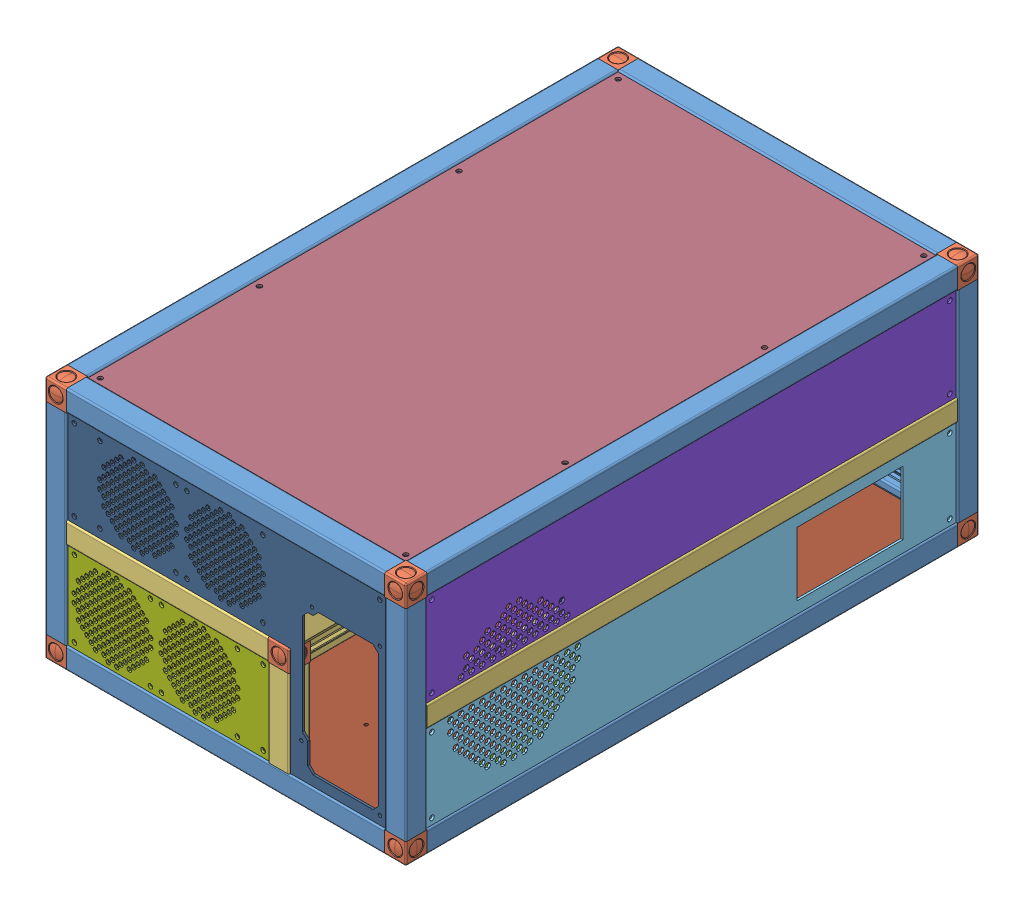
SolidWorks assembly Skeleton, configuration Default. Lengths in mm.
Overall size (341 231 541).
77 component instances, 16 part files, 227 mates.
Components (placement in the parent):
- BI010-A - BoschProfile 2NVS-20: BI010-A - BoschProfile 2NVS [L=300] at (-20 10 10) x (0 -1 0) z (-1 0 0) size (20 20 300)
- BI010-A - BoschProfile 2NVS-21: BI010-A - BoschProfile 2NVS [L=300] at (-20 10 530) x (0 0 1) z (-1 0 0) size (20 20 300)
- BI010-A - BoschProfile 2NVS-22: BI010-A - BoschProfile 2NVS [L=500] at (-10 10 20) size (20 20 500)
- BI010-A - BoschProfile 2NVS-23: BI010-A - BoschProfile 2NVS [L=500] at (-330 10 520) x (-1 0 0) z (0 0 -1) size (20 20 500)
- BI010-A - BoschProfile 2NVS-17: BI010-A - BoschProfile 2NVS [L=200] at (-330 -790 530) x (0 0 1) z (0 1 0) size (20 20 190)
- BI010-A - BoschProfile 2NVS-19: BI010-A - BoschProfile 2NVS [L=200] at (-10 -790 10) x (0 0 -1) z (0 1 0) size (20 20 190)
- BI010-A - BoschProfile 2NVS-18: BI010-A - BoschProfile 2NVS [L=200] at (-330 -790 10) x (-1 0 0) z (0 1 0) size (20 20 190)
- BI007-A - Cubic Connector 20x20-12: BI007-A - Cubic Connector 20x20 [Default] at (-20 10 10) x (-1 0 0) z (0 0 -1) size (33 33 33)
- BI007-A - Cubic Connector 20x20-13: BI007-A - Cubic Connector 20x20 [Default] at (-330 10 20) x (0 0 1) z (-1 0 0) size (33 33 33)
- BI010-A - BoschProfile 2NVS-13: BI010-A - BoschProfile 2NVS [L=200] at (-10 -790 530) x (1 0 0) z (0 1 0) size (20 20 190)
- BI007-A - Cubic Connector 20x20-7: BI007-A - Cubic Connector 20x20 [Default] at (-10 10 520) x (0 0 -1) z (1 0 0) size (33 33 33)
- BI007-A - Cubic Connector 20x20-8: BI007-A - Cubic Connector 20x20 [Default] at (-320 10 530) size (33 33 33)
- BI007-A - Cubic Connector 20x20-9: BI007-A - Cubic Connector 20x20 [Default] at (-10 220 520) x (0 0 -1) z (0 1 0) size (33 33 33)
- BI007-A - Cubic Connector 20x20-6: BI007-A - Cubic Connector 20x20 [Default] at (-320 220 530) x (1 0 0) z (0 1 0) size (33 33 33)
- BI007-A - Cubic Connector 20x20-10: BI007-A - Cubic Connector 20x20 [Default] at (-330 220 20) x (0 0 1) z (0 1 0) size (33 33 33)
- BI007-A - Cubic Connector 20x20-11: BI007-A - Cubic Connector 20x20 [Default] at (-20 220 10) x (-1 0 0) z (0 1 0) size (33 33 33)
- BI010-A - BoschProfile 2NVS-15: BI010-A - BoschProfile 2NVS [L=500] at (-10 220 20) x (0 1 0) z (0 0 1) size (20 20 500)
- BI010-A - BoschProfile 2NVS-14: BI010-A - BoschProfile 2NVS [L=500] at (-330 220 520) x (0 1 0) z (0 0 -1) size (20 20 500)
- BI010-A - BoschProfile 2NVS-12: BI010-A - BoschProfile 2NVS [L=300] at (-20 220 10) x (0 0 -1) z (-1 0 0) size (20 20 300)
- BI010-A - BoschProfile 2NVS-16: BI010-A - BoschProfile 2NVS [L=300] at (-20 220 530) x (0 1 0) z (-1 0 0) size (20 20 300)
- BI011-A - BoschProfile 3N-7: BI011-A - BoschProfile 3N [L = 300] at (-20 112 10) x (0 0 -1) z (-1 0 0) size (20 20 300)
- BI011-A - BoschProfile 3N-18: BI011-A - BoschProfile 3N [L = 500] at (-330 112 520) x (-1 0 0) z (0 0 -1) size (20 20 500)
- BI011-A - BoschProfile 3N-19: BI011-A - BoschProfile 3N [L = 82] at (-120 102 530) x (0 0 1) z (0 -1 0) size (20 20 82)
- BI011-A - BoschProfile 3N-20: BI011-A - BoschProfile 3N [L = 500] at (-120 112 520) x (0 1 0) z (0 0 -1) size (20 20 500)
- BI011-A - BoschProfile 3N-16: BI011-A - BoschProfile 3N [L = 180] at (-130 112 530) x (0 0 1) z (-1 0 0) size (20 20 190)
- BI007-A - Cubic Connector 20x20-14: BI007-A - Cubic Connector 20x20 [Default] at (-120 102 530) x (0 -1 0) z (1 0 0) size (33 33 33)
- BI011-A - BoschProfile 3N-17: BI011-A - BoschProfile 3N [L = 500] at (-10 112 520) x (1 0 0) z (0 0 -1) size (20 20 500)
- BI008-A - Bracket-S 20X20-21: BI008-A - Bracket-S 20X20 [Default] at (-320 122 530) x (0 0 -1) z (0 1 0) size (15.51 28.51 28.51)
- BI008-A - Bracket-S 20X20-22: BI008-A - Bracket-S 20X20 [Default] at (-130 20 530) x (0 0 -1) z (-1 0 0) size (15.51 28.51 28.51)
- BI008-A - Bracket-S 20X20-25: BI008-A - Bracket-S 20X20 [Default] at (-330 102 520) x (1 0 0) z (0 -1 0) size (15.51 28.51 28.51)
- BI008-A - Bracket-S 20X20-20: BI008-A - Bracket-S 20X20 [Default] at (-330 102 20) size (15.51 28.51 28.51)
- BI008-A - Bracket-S 20X20-23: BI008-A - Bracket-S 20X20 [Default] at (-10 102 20) x (-1 0 0) z (0 -1 0) size (15.51 28.51 28.51)
- BI008-A - Bracket-S 20X20-24: BI008-A - Bracket-S 20X20 [Default] at (-10 102 520) x (-1 0 0) z (0 0 -1) size (15.51 28.51 28.51)
- BI008-A - Bracket-S 20X20-18: BI008-A - Bracket-S 20X20 [Default] at (-20 102 10) x (0 0 1) z (-1 0 0) size (15.51 28.51 28.51)
- BI008-A - Bracket-S 20X20-17: BI008-A - Bracket-S 20X20 [Default] at (-320 102 10) x (0 0 1) z (0 -1 0) size (15.51 28.51 28.51)
- BI008-A - Bracket-S 20X20-15: BI008-A - Bracket-S 20X20 [Default] at (-130 112 20) x (0 1 0) z (-1 0 0) size (15.51 28.51 28.51)
- BI011-A - BoschProfile 3N-15: BI011-A - BoschProfile 3N [L = 300] at (-20 10 330) x (0 -1 0) z (-1 0 0) size (20 20 300)
- BI008-A - Bracket-S 20X20-16: BI008-A - Bracket-S 20X20 [Default] at (-320 10 340) x (0 1 0) z (0 0 1) size (15.51 28.51 28.51)
- BI008-A - Bracket-S 20X20-19: BI008-A - Bracket-S 20X20 [Default] at (-20 10 340) x (0 1 0) z (-1 0 0) size (15.51 28.51 28.51)
- CR020-A - PanelLaserBox1-1: CR020-A - PanelLaserBox1 [Default] at (-338.5 102 20) x (0 0 1) z (0 1 0) size (500 2 82)
- CR020-A - PanelLaserBox1-2: CR020-A - PanelLaserBox1 [FanSide] at (-1.5 102 520) x (0 0 -1) z (0 1 0) size (500 2 82)
- CR021-A - PanelLaserBox2-1: CR021-A - PanelLaserBox2 [Default] at (-320 20 1.5) x (1 0 0) z (0 -1 0) size (300 2 82)
- CR022-A - PanelLaserBox3-1: CR022-A - PanelLaserBox3 [Default] at (-320 20 536.5) x (1 0 0) z (0 -1 0) size (190 2 82)
- CR023-A - PanelLaserBox4-1: CR023-A - PanelLaserBox4 [FanSide] at (-3.5 210 20) x (0 0 1) z (0 1 0) size (500 2 88)
- CR023-A - PanelLaserBox4-2: CR023-A - PanelLaserBox4 [Default] at (-336.5 210 520) x (0 0 -1) z (0 1 0) size (500 2 88)
- CR024-A - PanelLaserBox5-1: CR024-A - PanelLaserBox5 [Default] at (-320 210 3.5) x (1 0 0) z (0 1 0) size (300 2 88)
- CR025-A - PanelLaserBox6-1: CR025-A - PanelLaserBox6 [Default] at (-110 122 536.5) x (1 0 0) z (0 -1 0) size (300 2 190)
- CR026-A - PanelLaserBox7-2: CR026-A - PanelLaserBox7 [Default] at (-170 22 270) x (0 0 -1) z (1 0 0) size (530 2 330)
- CR027-A - PanelLaserBox8-2: CR027-A - PanelLaserBox8 [Default] at (-170 124 270) x (0 0 -1) z (1 0 0) size (530 2 330)
- CR028-A - PanelLaserBox9-2: CR028-A - PanelLaserBox9 [Default] at (-170 228.5 270) x (0 0 -1) z (1 0 0) size (500 2 300)
- PP010-A - Plate Holder-57: PP010-A - Plate Holder [Default] at (-330 15.4 13.4) x (1 0 0) z (0 -1 0) size (12.3 11.8 14.6)
- PP010-A - Plate Holder-59: PP010-A - Plate Holder [Default] at (-330 15.4 501.6) x (1 0 0) z (0 -1 0) size (12.3 11.8 14.6)
- PP010-A - Plate Holder-58: PP010-A - Plate Holder [Default] at (-13.4 15.4 10) x (0 0 1) z (0 -1 0) size (12.3 11.8 14.6)
- PP010-A - Plate Holder-60: PP010-A - Plate Holder [Default] at (-10 15.4 526.6) x (-1 0 0) z (0 -1 0) size (12.3 11.8 14.6)
- PP010-A - Plate Holder-63: PP010-A - Plate Holder [Default] at (-330 117.4 13.4) x (1 0 0) z (0 -1 0) size (12.3 11.8 14.6)
- PP010-A - Plate Holder-61: PP010-A - Plate Holder [Default] at (-13.4 117.4 10) x (0 0 1) z (0 -1 0) size (12.3 11.8 14.6)
- PP010-A - Plate Holder-62: PP010-A - Plate Holder [Default] at (-10 117.4 526.6) x (-1 0 0) z (0 -1 0) size (12.3 11.8 14.6)
- PP010-A - Plate Holder-73: PP010-A - Plate Holder [Default] at (-15.4 220 526.6) x (0 -1 0) z (1 0 0) size (12.3 11.8 14.6)
- PP010-A - Plate Holder-74: PP010-A - Plate Holder [Default] at (-324.6 220 13.4) x (0 -1 0) z (-1 0 0) size (12.3 11.8 14.6)
- PP010-A - Plate Holder-68: PP010-A - Plate Holder [Default] at (-326.6 214.6 10) x (0 0 1) z (0 1 0) size (12.3 11.8 14.6)
- PP010-A - Plate Holder-75: PP010-A - Plate Holder [Default] at (-13.4 214.6 530) x (0 0 -1) z (0 1 0) size (12.3 11.8 14.6)
- PP010-A - Plate Holder-67: PP010-A - Plate Holder [Default] at (-330 214.6 526.6) x (1 0 0) z (0 1 0) size (12.3 11.8 14.6)
- PP010-A - Plate Holder-69: PP010-A - Plate Holder [Default] at (-10 214.6 13.4) x (-1 0 0) z (0 1 0) size (12.3 11.8 14.6)
- PP010-A - Plate Holder-64: PP010-A - Plate Holder [Default] at (-123.4 106.6 530) x (0 0 -1) z (0 1 0) size (12.3 11.8 14.6)
- PP010-A - Plate Holder-65: PP010-A - Plate Holder [Default] at (-301.6 15.4 10) x (0 0 1) z (0 -1 0) size (12.3 11.8 14.6)
- PP010-A - Plate Holder-72: PP010-A - Plate Holder [Default] at (-301.6 117.4 10) x (0 0 1) z (0 -1 0) size (12.3 11.8 14.6)
- PP010-A - Plate Holder-70: PP010-A - Plate Holder [Default] at (-38.4 214.6 10) x (0 0 1) z (0 1 0) size (12.3 11.8 14.6)
- PP010-A - Plate Holder-71: PP010-A - Plate Holder [Default] at (-10 15.4 38.4) x (-1 0 0) z (0 -1 0) size (12.3 11.8 14.6)
- PP010-A - Plate Holder-66: PP010-A - Plate Holder [Default] at (-10 117.4 38.4) x (-1 0 0) z (0 -1 0) size (12.3 11.8 14.6)
- PP010-A - Plate Holder-41: PP010-A - Plate Holder [Default] at (-10 214.6 501.6) x (-1 0 0) z (0 1 0) size (12.3 11.8 14.6)
- PP010-A - Plate Holder-43: PP010-A - Plate Holder [Default] at (-301.6 214.6 530) x (0 0 -1) z (0 1 0) size (12.3 11.8 14.6)
- PP010-A - Plate Holder-54: PP010-A - Plate Holder [Default] at (-330 117.4 501.6) x (1 0 0) z (0 -1 0) size (12.3 11.8 14.6)
- PP010-A - Plate Holder-55: PP010-A - Plate Holder [Default] at (-330 214.6 38.4) x (1 0 0) z (0 1 0) size (12.3 11.8 14.6)
- PP010-A - Plate Holder-56: PP010-A - Plate Holder [Default] at (-324.6 220 501.6) x (0 -1 0) z (-1 0 0) size (12.3 11.8 14.6)
- PP010-A - Plate Holder-53: PP010-A - Plate Holder [Default] at (-15.4 220 38.4) x (0 -1 0) z (1 0 0) size (12.3 11.8 14.6)
- PP011-A - PSU Fan Guide Top-1: PP011-A - PSU Fan Guide Top [Default] at (-16.5 97 436.5) x (0 0 -1) z (0 -1 0) size (142.7 16 46)
- PP012-A - PSU Fan Guide Bottom-1: PP012-A - PSU Fan Guide Bottom [Default] at (-16.5 102 436.5) x (0 0 -1) z (0 -1 0) size (148.33 16.5 75.99)
Mates (geometry in assembly coordinates):
- Coincident77: coincident: plane of BI007-A - Cubic Connector 20x20-12 through (-10 10 0) normal (0 0 -1); plane of assembly through (0 0 0) normal (0 0 1)
- Coincident78: coincident: plane of BI007-A - Cubic Connector 20x20-12 through (-10 0 10) normal (0 -1 0); plane of assembly through (0 0 0) normal (0 1 0)
- Coincident79: coincident: plane of BI007-A - Cubic Connector 20x20-12 through (0 10 10) normal (1 0 0); plane of assembly through (0 0 0) normal (1 0 0)
- Coincident80: coincident: plane of BI010-A - BoschProfile 2NVS-20 through (-1020 18.5 0) normal (0 0 -1); plane of BI007-A - Cubic Connector 20x20-12 through (-10 10 0) normal (0 0 -1)
- Coincident81: coincident: plane of BI010-A - BoschProfile 2NVS-20 through (-20 18.5 18.5) normal (1 0 0); plane of BI007-A - Cubic Connector 20x20-12 through (-20 10 10) normal (-1 0 0)
- Coincident82: coincident: plane of BI010-A - BoschProfile 2NVS-20 through (-1020 0 1.5) normal (0 -1 0); plane of BI007-A - Cubic Connector 20x20-12 through (-10 0 10) normal (0 -1 0)
- Coincident83: coincident: plane of BI010-A - BoschProfile 2NVS-22 through (0 1.5 1020) normal (1 0 0); plane of BI007-A - Cubic Connector 20x20-12 through (0 10 10) normal (1 0 0)
- Coincident84: coincident: plane of BI010-A - BoschProfile 2NVS-22 through (-18.5 0 1020) normal (0 -1 0); plane of BI007-A - Cubic Connector 20x20-12 through (-10 0 10) normal (0 -1 0)
- Coincident85: coincident: plane of BI010-A - BoschProfile 2NVS-22 through (-18.5 18.5 20) normal (0 0 -1); plane of BI007-A - Cubic Connector 20x20-12 through (-10 10 20) normal (0 0 1)
- Coincident86: coincident: plane of BI010-A - BoschProfile 2NVS-19 through (-1.5 210 0) normal (0 0 -1); plane of BI007-A - Cubic Connector 20x20-12 through (-10 10 0) normal (0 0 -1)
- Coincident87: coincident: plane of BI010-A - BoschProfile 2NVS-19 through (0 210 18.5) normal (1 0 0); plane of BI007-A - Cubic Connector 20x20-12 through (0 10 10) normal (1 0 0)
- Coincident88: coincident: plane of BI010-A - BoschProfile 2NVS-19 through (-18.5 20 18.5) normal (0 -1 0); plane of BI007-A - Cubic Connector 20x20-12 through (-10 20 10) normal (0 1 0)
- Coincident89: coincident: plane of BI010-A - BoschProfile 2NVS-20 through (-1020 18.5 0) normal (0 0 -1); plane of BI007-A - Cubic Connector 20x20-13 through (-330 10 0) normal (0 0 -1)
- Coincident90: coincident: plane of BI010-A - BoschProfile 2NVS-20 through (-1020 0 1.5) normal (0 -1 0); plane of BI007-A - Cubic Connector 20x20-13 through (-330 0 10) normal (0 -1 0)
- Coincident91: coincident: plane of BI010-A - BoschProfile 2NVS-20 through (-320 18.5 18.5) normal (-1 0 0); plane of BI007-A - Cubic Connector 20x20-13 through (-320 10 10) normal (1 0 0)
- Coincident92: coincident: plane of BI010-A - BoschProfile 2NVS-23 through (-321.5 18.5 20) normal (0 0 -1); plane of BI007-A - Cubic Connector 20x20-13 through (-330 10 20) normal (0 0 1)
- Coincident93: coincident: plane of BI010-A - BoschProfile 2NVS-23 through (-340 1.5 -480) normal (-1 0 0); plane of BI007-A - Cubic Connector 20x20-13 through (-340 10 10) normal (-1 0 0)
- Coincident94: coincident: plane of BI010-A - BoschProfile 2NVS-23 through (-321.5 0 -480) normal (0 -1 0); plane of BI007-A - Cubic Connector 20x20-13 through (-330 0 10) normal (0 -1 0)
- Coincident95: coincident: plane of BI010-A - BoschProfile 2NVS-22 through (0 1.5 1020) normal (1 0 0); plane of BI007-A - Cubic Connector 20x20-7 through (0 10 530) normal (1 0 0)
- Coincident96: coincident: plane of BI010-A - BoschProfile 2NVS-22 through (-18.5 18.5 520) normal (0 0 1); plane of BI007-A - Cubic Connector 20x20-7 through (-10 10 520) normal (0 0 -1)
- Coincident97: coincident: plane of BI010-A - BoschProfile 2NVS-22 through (-18.5 0 1020) normal (0 -1 0); plane of BI007-A - Cubic Connector 20x20-7 through (-10 0 530) normal (0 -1 0)
- Coincident98: coincident: plane of BI010-A - BoschProfile 2NVS-21 through (-20 18.5 521.5) normal (1 0 0); plane of BI007-A - Cubic Connector 20x20-7 through (-20 10 530) normal (-1 0 0)
- Coincident99: coincident: plane of BI010-A - BoschProfile 2NVS-21 through (-1020 1.5 540) normal (0 0 1); plane of BI007-A - Cubic Connector 20x20-7 through (-10 10 540) normal (0 0 1)
- Coincident100: coincident: plane of BI010-A - BoschProfile 2NVS-21 through (-1020 0 521.5) normal (0 -1 0); plane of BI007-A - Cubic Connector 20x20-7 through (-10 0 530) normal (0 -1 0)
- Coincident101: coincident: plane of BI010-A - BoschProfile 2NVS-23 through (-321.5 0 -480) normal (0 -1 0); plane of BI007-A - Cubic Connector 20x20-8 through (-330 0 530) normal (0 -1 0)
- Coincident102: coincident: plane of BI010-A - BoschProfile 2NVS-23 through (-321.5 18.5 520) normal (0 0 1); plane of BI007-A - Cubic Connector 20x20-8 through (-330 10 520) normal (0 0 -1)
- Coincident103: coincident: plane of BI010-A - BoschProfile 2NVS-23 through (-340 1.5 -480) normal (-1 0 0); plane of BI007-A - Cubic Connector 20x20-8 through (-340 10 530) normal (-1 0 0)
- Coincident104: coincident: plane of BI010-A - BoschProfile 2NVS-13 through (0 210 538.5) normal (1 0 0); plane of BI007-A - Cubic Connector 20x20-7 through (0 10 530) normal (1 0 0)
- Coincident105: coincident: plane of BI010-A - BoschProfile 2NVS-13 through (-18.5 210 540) normal (0 0 1); plane of BI007-A - Cubic Connector 20x20-7 through (-10 10 540) normal (0 0 1)
- Coincident106: coincident: plane of BI010-A - BoschProfile 2NVS-13 through (-18.5 20 521.5) normal (0 -1 0); plane of BI007-A - Cubic Connector 20x20-7 through (-10 20 530) normal (0 1 0)
- Coincident107: coincident: plane of BI010-A - BoschProfile 2NVS-17 through (-338.5 210 540) normal (0 0 1); plane of BI007-A - Cubic Connector 20x20-8 through (-330 10 540) normal (0 0 1)
- Coincident108: coincident: plane of BI010-A - BoschProfile 2NVS-17 through (-340 210 521.5) normal (-1 0 0); plane of BI007-A - Cubic Connector 20x20-8 through (-340 10 530) normal (-1 0 0)
- Coincident109: coincident: plane of BI010-A - BoschProfile 2NVS-17 through (-321.5 20 521.5) normal (0 -1 0); plane of BI007-A - Cubic Connector 20x20-8 through (-330 20 530) normal (0 1 0)
- Coincident110: coincident: plane of BI010-A - BoschProfile 2NVS-18 through (-321.5 210 0) normal (0 0 -1); plane of BI007-A - Cubic Connector 20x20-13 through (-330 10 0) normal (0 0 -1)
- Coincident111: coincident: plane of BI010-A - BoschProfile 2NVS-18 through (-340 210 1.5) normal (-1 0 0); plane of BI007-A - Cubic Connector 20x20-13 through (-340 10 10) normal (-1 0 0)
- Coincident112: coincident: plane of BI010-A - BoschProfile 2NVS-18 through (-321.5 20 18.5) normal (0 -1 0); plane of BI007-A - Cubic Connector 20x20-13 through (-330 20 10) normal (0 1 0)
- Coincident113: coincident: plane of BI010-A - BoschProfile 2NVS-13 through (0 210 538.5) normal (1 0 0); plane of BI007-A - Cubic Connector 20x20-9 through (0 220 530) normal (1 0 0)
- Coincident114: coincident: plane of BI010-A - BoschProfile 2NVS-13 through (-18.5 210 540) normal (0 0 1); plane of BI007-A - Cubic Connector 20x20-9 through (-10 220 540) normal (0 0 1)
- Coincident115: coincident: plane of BI010-A - BoschProfile 2NVS-13 through (-18.5 210 521.5) normal (0 1 0); plane of BI007-A - Cubic Connector 20x20-9 through (-10 210 530) normal (0 -1 0)
- Coincident116: coincident: plane of BI010-A - BoschProfile 2NVS-13 through (-18.5 210 521.5) normal (0 1 0); plane of BI007-A - Cubic Connector 20x20-6 through (-330 210 530) normal (0 -1 0)
- Coincident118: coincident: plane of BI010-A - BoschProfile 2NVS-17 through (-338.5 210 540) normal (0 0 1); plane of BI007-A - Cubic Connector 20x20-6 through (-330 220 540) normal (0 0 1)
- Coincident119: coincident: plane of BI010-A - BoschProfile 2NVS-17 through (-340 210 521.5) normal (-1 0 0); plane of BI007-A - Cubic Connector 20x20-6 through (-340 220 530) normal (-1 0 0)
- Coincident120: coincident: plane of BI010-A - BoschProfile 2NVS-13 through (-18.5 210 521.5) normal (0 1 0); plane of BI007-A - Cubic Connector 20x20-10 through (-330 210 10) normal (0 -1 0)
- Coincident124: coincident: plane of BI010-A - BoschProfile 2NVS-18 through (-340 210 1.5) normal (-1 0 0); plane of BI007-A - Cubic Connector 20x20-10 through (-340 220 10) normal (-1 0 0)
- Coincident125: coincident: plane of BI010-A - BoschProfile 2NVS-18 through (-321.5 210 0) normal (0 0 -1); plane of BI007-A - Cubic Connector 20x20-10 through (-330 220 0) normal (0 0 -1)
- Coincident126: coincident: plane of BI010-A - BoschProfile 2NVS-13 through (-18.5 210 521.5) normal (0 1 0); plane of BI007-A - Cubic Connector 20x20-11 through (-10 210 10) normal (0 -1 0)
- Coincident127: coincident: plane of BI010-A - BoschProfile 2NVS-19 through (-1.5 210 0) normal (0 0 -1); plane of BI007-A - Cubic Connector 20x20-11 through (-10 220 0) normal (0 0 -1)
- Coincident128: coincident: plane of BI010-A - BoschProfile 2NVS-19 through (0 210 18.5) normal (1 0 0); plane of BI007-A - Cubic Connector 20x20-11 through (0 220 10) normal (1 0 0)
- Coincident130: coincident: plane of BI007-A - Cubic Connector 20x20-9 through (0 220 530) normal (1 0 0); plane of BI010-A - BoschProfile 2NVS-15 through (0 211.5 1020) normal (1 0 0)
- Coincident131: coincident: plane of BI007-A - Cubic Connector 20x20-9 through (-10 230 530) normal (0 1 0); plane of BI010-A - BoschProfile 2NVS-15 through (-1.5 230 1020) normal (0 1 0)
- Coincident132: coincident: plane of BI007-A - Cubic Connector 20x20-11 through (-10 220 20) normal (0 0 1); plane of BI010-A - BoschProfile 2NVS-15 through (-18.5 211.5 20) normal (0 0 -1)
- Coincident133: coincident: plane of BI007-A - Cubic Connector 20x20-10 through (-330 230 10) normal (0 1 0); plane of BI010-A - BoschProfile 2NVS-14 through (-338.5 230 -480) normal (0 1 0)
- Coincident134: coincident: plane of BI007-A - Cubic Connector 20x20-10 through (-340 220 10) normal (-1 0 0); plane of BI010-A - BoschProfile 2NVS-14 through (-340 211.5 -480) normal (-1 0 0)
- Coincident135: coincident: plane of BI007-A - Cubic Connector 20x20-10 through (-330 220 20) normal (0 0 1); plane of BI010-A - BoschProfile 2NVS-14 through (-321.5 211.5 20) normal (0 0 -1)
- Coincident136: coincident: plane of BI007-A - Cubic Connector 20x20-10 through (-330 220 0) normal (0 0 -1); plane of BI010-A - BoschProfile 2NVS-12 through (-1020 228.5 0) normal (0 0 -1)
- Coincident137: coincident: plane of BI007-A - Cubic Connector 20x20-10 through (-330 230 10) normal (0 1 0); plane of BI010-A - BoschProfile 2NVS-12 through (-1020 230 18.5) normal (0 1 0)
- Coincident138: coincident: plane of BI007-A - Cubic Connector 20x20-11 through (-20 220 10) normal (-1 0 0); plane of BI010-A - BoschProfile 2NVS-12 through (-20 211.5 18.5) normal (1 0 0)
- Coincident139: coincident: plane of BI007-A - Cubic Connector 20x20-6 through (-330 220 540) normal (0 0 1); plane of BI010-A - BoschProfile 2NVS-16 through (-1020 211.5 540) normal (0 0 1)
- Coincident140: coincident: plane of BI007-A - Cubic Connector 20x20-6 through (-330 230 530) normal (0 1 0); plane of BI010-A - BoschProfile 2NVS-16 through (-1020 230 538.5) normal (0 1 0)
- Coincident141: coincident: plane of BI007-A - Cubic Connector 20x20-9 through (-20 220 530) normal (-1 0 0); plane of BI010-A - BoschProfile 2NVS-16 through (-20 211.5 521.5) normal (1 0 0)
- Coincident154: coincident: plane of BI010-A - BoschProfile 2NVS-21 through (-1020 1.5 540) normal (0 0 1); plane of BI011-A - BoschProfile 3N-19 through (-111.5 -2898 540) normal (0 0 1)
- Coincident155: coincident: plane of BI010-A - BoschProfile 2NVS-21 through (-1020 20 538.5) normal (0 1 0); plane of BI011-A - BoschProfile 3N-19 through (-111.5 20 538.5) normal (0 -1 0)
- Coincident156: coincident: plane of BI010-A - BoschProfile 2NVS-19 through (-1.5 210 0) normal (0 0 -1); plane of BI011-A - BoschProfile 3N-7 through (-3020 120.5 0) normal (0 0 -1)
- Width5: width: plane of BI010-A - BoschProfile 2NVS-18 through (-340 210 1.5) normal (-1 0 0); plane of BI010-A - BoschProfile 2NVS-19 through (0 210 18.5) normal (1 0 0); plane of BI011-A - BoschProfile 3N-7 through (-320 120.5 1.5) normal (-1 0 0); plane of BI011-A - BoschProfile 3N-7 through (-20 120.5 1.5) normal (1 0 0)
- Coincident158: coincident: plane of BI010-A - BoschProfile 2NVS-18 through (-340 210 1.5) normal (-1 0 0); plane of BI011-A - BoschProfile 3N-18 through (-340 103.5 -2480) normal (-1 0 0)
- Width6: width: plane of BI010-A - BoschProfile 2NVS-18 through (-321.5 210 0) normal (0 0 -1); plane of BI010-A - BoschProfile 2NVS-17 through (-338.5 210 540) normal (0 0 1); plane of BI011-A - BoschProfile 3N-18 through (-338.5 103.5 20) normal (0 0 -1); plane of BI011-A - BoschProfile 3N-18 through (-338.5 103.5 520) normal (0 0 1)
- Coincident159: coincident: plane of BI011-A - BoschProfile 3N-7 through (-3020 122 6.5) normal (0 1 0); plane of BI011-A - BoschProfile 3N-18 through (-338.5 122 -2480) normal (0 1 0)
- Coincident160: coincident: plane of BI011-A - BoschProfile 3N-18 through (-338.5 122 -2480) normal (0 1 0); plane of BI011-A - BoschProfile 3N-20 through (-128.5 122 -2480) normal (0 1 0)
- Coincident161: coincident: plane of BI011-A - BoschProfile 3N-7 through (-3020 115.5 20) normal (0 0 1); plane of BI011-A - BoschProfile 3N-20 through (-128.5 120.5 20) normal (0 0 -1)
- Coincident162: coincident: plane of BI011-A - BoschProfile 3N-19 through (-130 -2898 526.5) normal (-1 0 0); plane of BI011-A - BoschProfile 3N-20 through (-130 115.5 -2480) normal (-1 0 0)
- Distance15: distance = 90 mm: plane of BI011-A - BoschProfile 3N-19 through (-110 -2898 533.5) normal (1 0 0); plane of BI010-A - BoschProfile 2NVS-13 through (-20 210 533.5) normal (-1 0 0)
- Coincident163: coincident: plane of BI011-A - BoschProfile 3N-19 through (-111.5 -2898 540) normal (0 0 1); plane of BI011-A - BoschProfile 3N-16 through (-3130 103.5 540) normal (0 0 1)
- Coincident164: coincident: plane of BI010-A - BoschProfile 2NVS-17 through (-320 210 538.5) normal (1 0 0); plane of BI011-A - BoschProfile 3N-16 through (-320 103.5 538.5) normal (-1 0 0)
- Coincident165: coincident: plane of BI011-A - BoschProfile 3N-20 through (-128.5 122 -2480) normal (0 1 0); plane of BI011-A - BoschProfile 3N-16 through (-3130 122 538.5) normal (0 1 0)
- Coincident166: coincident: plane of BI011-A - BoschProfile 3N-19 through (-111.5 -2898 540) normal (0 0 1); plane of BI007-A - Cubic Connector 20x20-14 through (-120 112 540) normal (0 0 1)
- Coincident167: coincident: plane of BI011-A - BoschProfile 3N-20 through (-128.5 122 -2480) normal (0 1 0); plane of BI007-A - Cubic Connector 20x20-14 through (-120 122 530) normal (0 1 0)
- Coincident168: coincident: plane of BI011-A - BoschProfile 3N-19 through (-110 -2898 533.5) normal (1 0 0); plane of BI007-A - Cubic Connector 20x20-14 through (-110 112 530) normal (1 0 0)
- Coincident171: coincident: plane of BI011-A - BoschProfile 3N-7 through (-3020 122 6.5) normal (0 1 0); plane of BI011-A - BoschProfile 3N-17 through (-6.5 122 -2480) normal (0 1 0)
- Coincident172: coincident: plane of BI010-A - BoschProfile 2NVS-13 through (-1.5 210 520) normal (0 0 -1); plane of BI011-A - BoschProfile 3N-17 through (-1.5 120.5 520) normal (0 0 1)
- Coincident177: coincident: plane of BI011-A - BoschProfile 3N-19 through (-111.5 102 538.5) normal (0 1 0); plane of BI007-A - Cubic Connector 20x20-14 through (-120 102 530) normal (0 -1 0)
- Coincident178: coincident: plane of BI008-A - Bracket-S 20X20-21 through (-312.207 129.793 536.5) normal (0 0 1); plane of BI008-A - Bracket-S 20X20-22 through (-137.793 27.793 536.5) normal (0 0 1)
- Coincident179: coincident: plane of BI011-A - BoschProfile 3N-19 through (-130 -2898 538.5) normal (-1 0 0); plane of BI008-A - Bracket-S 20X20-22 through (-130 20.5 536.5) normal (1 0 0)
- Coincident180: coincident: plane of BI010-A - BoschProfile 2NVS-21 through (-1020 20 538.5) normal (0 1 0); plane of BI008-A - Bracket-S 20X20-22 through (-153.5 20 536.5) normal (0 -1 0)
- Distance17: distance = 1 mm: plane of BI008-A - Bracket-S 20X20-25 through (-321 94.207 512.207) normal (1 0 0); plane of BI011-A - BoschProfile 3N-18 through (-320 108.5 -2480) normal (1 0 0)
- Coincident181: coincident: plane of BI011-A - BoschProfile 3N-18 through (-333.5 102 -2480) normal (0 -1 0); plane of BI008-A - Bracket-S 20X20-25 through (-336.5 102 519.5) normal (0 1 0)
- Coincident182: coincident: plane of BI010-A - BoschProfile 2NVS-17 through (-333.5 210 520) normal (0 0 -1); plane of BI008-A - Bracket-S 20X20-25 through (-336.5 78.5 520) normal (0 0 1)
- Distance18: distance = 1 mm: plane of BI008-A - Bracket-S 20X20-20 through (-321 94.207 27.793) normal (1 0 0); plane of BI011-A - BoschProfile 3N-18 through (-320 108.5 -2480) normal (1 0 0)
- Coincident183: coincident: plane of BI010-A - BoschProfile 2NVS-18 through (-338.5 210 20) normal (0 0 1); plane of BI008-A - Bracket-S 20X20-20 through (-336.5 101.5 20) normal (0 0 -1)
- Coincident184: coincident: plane of BI011-A - BoschProfile 3N-18 through (-333.5 102 -2480) normal (0 -1 0); plane of BI008-A - Bracket-S 20X20-20 through (-336.5 102 43.5) normal (0 1 0)
- Coincident185: coincident: plane of BI010-A - BoschProfile 2NVS-13 through (0 210 538.5) normal (1 0 0); plane of BI011-A - BoschProfile 3N-17 through (0 120.5 -2480) normal (1 0 0)
- Distance21: distance = 1 mm: plane of BI008-A - Bracket-S 20X20-23 through (-19 94.207 27.793) normal (-1 0 0); plane of BI011-A - BoschProfile 3N-17 through (-20 103.5 -2480) normal (-1 0 0)
- Coincident186: coincident: plane of BI011-A - BoschProfile 3N-17 through (-1.5 102 -2480) normal (0 -1 0); plane of BI008-A - Bracket-S 20X20-23 through (-3.5 102 20.5) normal (0 1 0)
- Coincident187: coincident: plane of BI010-A - BoschProfile 2NVS-19 through (-6.5 210 20) normal (0 0 1); plane of BI008-A - Bracket-S 20X20-23 through (-3.5 78.5 20) normal (0 0 -1)
- Distance22: distance = 1 mm: plane of BI008-A - Bracket-S 20X20-24 through (-19 94.207 512.207) normal (-1 0 0); plane of BI011-A - BoschProfile 3N-17 through (-20 115.5 -2480) normal (-1 0 0)
- Coincident188: coincident: plane of BI010-A - BoschProfile 2NVS-13 through (-13.5 210 520) normal (0 0 -1); plane of BI008-A - Bracket-S 20X20-24 through (-3.5 101.5 520) normal (0 0 1)
- Coincident189: coincident: plane of BI011-A - BoschProfile 3N-17 through (-13.5 102 -2480) normal (0 -1 0); plane of BI008-A - Bracket-S 20X20-24 through (-3.5 102 496.5) normal (0 1 0)
- Distance24: distance = 1 mm: plane of BI008-A - Bracket-S 20X20-18 through (-27.793 94.207 19) normal (0 0 1); plane of BI011-A - BoschProfile 3N-7 through (-3020 103.5 20) normal (0 0 1)
- Coincident192: coincident: plane of BI011-A - BoschProfile 3N-7 through (-3020 102 1.5) normal (0 -1 0); plane of BI008-A - Bracket-S 20X20-18 through (-43.5 102 3.5) normal (0 1 0)
- Coincident193: coincident: plane of BI010-A - BoschProfile 2NVS-19 through (-20 210 1.5) normal (-1 0 0); plane of BI008-A - Bracket-S 20X20-18 through (-20 101.5 3.5) normal (1 0 0)
- Coincident194: coincident: plane of BI008-A - Bracket-S 20X20-18 through (-27.793 94.207 3.5) normal (0 0 -1); plane of BI008-A - Bracket-S 20X20-17 through (-312.207 94.207 3.5) normal (0 0 -1)
- Coincident195: coincident: plane of BI011-A - BoschProfile 3N-7 through (-3020 102 1.5) normal (0 -1 0); plane of BI008-A - Bracket-S 20X20-17 through (-319.5 102 3.5) normal (0 1 0)
- Coincident196: coincident: plane of BI010-A - BoschProfile 2NVS-18 through (-320 210 6.5) normal (1 0 0); plane of BI008-A - Bracket-S 20X20-17 through (-320 78.5 3.5) normal (-1 0 0)
- Coincident197: coincident: plane of BI011-A - BoschProfile 3N-20 through (-130 115.5 -2480) normal (-1 0 0); plane of BI008-A - Bracket-S 20X20-15 through (-130 105.5 20.5) normal (1 0 0)
- Coincident198: coincident: plane of BI011-A - BoschProfile 3N-7 through (-3020 115.5 20) normal (0 0 1); plane of BI008-A - Bracket-S 20X20-15 through (-153.5 105.5 20) normal (0 0 -1)
- Distance26: distance = 1 mm: plane of BI008-A - Bracket-S 20X20-15 through (-137.793 121 27.793) normal (0 1 0); plane of BI011-A - BoschProfile 3N-20 through (-128.5 122 -2480) normal (0 1 0)
- Coincident199: coincident: plane of BI010-A - BoschProfile 2NVS-22 through (-18.5 0 1020) normal (0 -1 0); plane of BI011-A - BoschProfile 3N-15 through (-3020 0 321.5) normal (0 -1 0)
- Width9: width: plane of BI010-A - BoschProfile 2NVS-22 through (0 1.5 1020) normal (1 0 0); plane of BI010-A - BoschProfile 2NVS-23 through (-340 1.5 -480) normal (-1 0 0); plane of BI011-A - BoschProfile 3N-15 through (-20 1.5 321.5) normal (1 0 0); plane of BI011-A - BoschProfile 3N-15 through (-320 1.5 321.5) normal (-1 0 0)
- Distance27: distance = 200 mm: plane of BI011-A - BoschProfile 3N-15 through (-3020 13.5 340) normal (0 0 1); plane of BI010-A - BoschProfile 2NVS-21 through (-1020 1.5 540) normal (0 0 1)
- Coincident200: coincident: plane of BI010-A - BoschProfile 2NVS-23 through (-320 18.5 -480) normal (1 0 0); plane of BI008-A - Bracket-S 20X20-16 through (-320 3.5 363.5) normal (-1 0 0)
- Coincident201: coincident: plane of BI011-A - BoschProfile 3N-15 through (-3020 1.5 340) normal (0 0 1); plane of BI008-A - Bracket-S 20X20-16 through (-319.5 3.5 340) normal (0 0 -1)
- Distance28: distance = 1 mm: plane of BI008-A - Bracket-S 20X20-16 through (-312.207 19 347.793) normal (0 1 0); plane of BI011-A - BoschProfile 3N-15 through (-3020 20 338.5) normal (0 1 0)
- Coincident202: coincident: plane of BI008-A - Bracket-S 20X20-16 through (-312.207 19 347.793) normal (0 1 0); plane of BI008-A - Bracket-S 20X20-19 through (-27.793 19 347.793) normal (0 1 0)
- Coincident203: coincident: plane of BI010-A - BoschProfile 2NVS-22 through (-20 18.5 1020) normal (-1 0 0); plane of BI008-A - Bracket-S 20X20-19 through (-20 3.5 340.5) normal (1 0 0)
- Coincident204: coincident: plane of BI011-A - BoschProfile 3N-15 through (-3020 13.5 340) normal (0 0 1); plane of BI008-A - Bracket-S 20X20-19 through (-43.5 3.5 340) normal (0 0 -1)
- Coincident205: coincident: plane of BI008-A - Bracket-S 20X20-20 through (-336.5 94.207 27.793) normal (-1 0 0); plane of CR020-A - PanelLaserBox1-1 through (-336.5 102 20) normal (1 0 0)
- Width10: width: plane of BI011-A - BoschProfile 3N-18 through (-333.5 102 -2480) normal (0 -1 0); plane of BI010-A - BoschProfile 2NVS-23 through (-338.5 20 -480) normal (0 1 0); plane of CR020-A - PanelLaserBox1-1 through (-336.5 20 20) normal (0 -1 0); plane of CR020-A - PanelLaserBox1-1 through (-336.5 102 20) normal (0 1 0)
- Width11: width: plane of BI010-A - BoschProfile 2NVS-17 through (-333.5 210 520) normal (0 0 -1); plane of BI010-A - BoschProfile 2NVS-18 through (-338.5 210 20) normal (0 0 1); plane of CR020-A - PanelLaserBox1-1 through (-336.5 102 20) normal (0 0 -1); plane of CR020-A - PanelLaserBox1-1 through (-336.5 102 520) normal (0 0 1)
- Coincident206: coincident: plane of BI008-A - Bracket-S 20X20-24 through (-3.5 94.207 512.207) normal (1 0 0); plane of CR020-A - PanelLaserBox1-2 through (-3.5 102 520) normal (-1 0 0)
- Width12: width: plane of BI010-A - BoschProfile 2NVS-13 through (-1.5 210 520) normal (0 0 -1); plane of BI010-A - BoschProfile 2NVS-19 through (-6.5 210 20) normal (0 0 1); plane of CR020-A - PanelLaserBox1-2 through (-3.5 102 20) normal (0 0 -1); plane of CR020-A - PanelLaserBox1-2 through (-3.5 102 520) normal (0 0 1)
- Width13: width: plane of BI010-A - BoschProfile 2NVS-22 through (-1.5 20 1020) normal (0 1 0); plane of BI011-A - BoschProfile 3N-17 through (-1.5 102 -2480) normal (0 -1 0); plane of CR020-A - PanelLaserBox1-2 through (-3.5 102 520) normal (0 1 0); plane of CR020-A - PanelLaserBox1-2 through (-3.5 20 520) normal (0 -1 0)
- Coincident207: coincident: plane of BI008-A - Bracket-S 20X20-18 through (-27.793 94.207 3.5) normal (0 0 -1); plane of CR021-A - PanelLaserBox2-1 through (-320 20 3.5) normal (0 0 1)
- Width14: width: plane of BI010-A - BoschProfile 2NVS-19 through (-20 210 1.5) normal (-1 0 0); plane of BI010-A - BoschProfile 2NVS-18 through (-320 210 6.5) normal (1 0 0); plane of CR021-A - PanelLaserBox2-1 through (-20 20 3.5) normal (1 0 0); plane of CR021-A - PanelLaserBox2-1 through (-320 20 3.5) normal (-1 0 0)
- Width15: width: plane of BI011-A - BoschProfile 3N-7 through (-3020 102 1.5) normal (0 -1 0); plane of BI010-A - BoschProfile 2NVS-20 through (-1020 20 6.5) normal (0 1 0); plane of CR021-A - PanelLaserBox2-1 through (-320 102 3.5) normal (0 1 0); plane of CR021-A - PanelLaserBox2-1 through (-320 20 3.5) normal (0 -1 0)
- Coincident208: coincident: plane of BI008-A - Bracket-S 20X20-21 through (-312.207 129.793 536.5) normal (0 0 1); plane of CR022-A - PanelLaserBox3-1 through (-320 20 536.5) normal (0 0 -1)
- Width16: width: plane of BI011-A - BoschProfile 3N-16 through (-3130 102 533.5) normal (0 -1 0); plane of BI010-A - BoschProfile 2NVS-21 through (-1020 20 538.5) normal (0 1 0); plane of CR022-A - PanelLaserBox3-1 through (-320 20 538.5) normal (0 -1 0); plane of CR022-A - PanelLaserBox3-1 through (-320 102 538.5) normal (0 1 0)
- Width17: width: plane of BI011-A - BoschProfile 3N-19 through (-130 -2898 538.5) normal (-1 0 0); plane of BI010-A - BoschProfile 2NVS-17 through (-320 210 538.5) normal (1 0 0); plane of CR022-A - PanelLaserBox3-1 through (-320 20 538.5) normal (-1 0 0); plane of CR022-A - PanelLaserBox3-1 through (-130 20 538.5) normal (1 0 0)
- Coincident209: coincident: plane of CR020-A - PanelLaserBox1-2 through (-1.5 102 520) normal (1 0 0); plane of CR023-A - PanelLaserBox4-1 through (-1.5 210 20) normal (1 0 0)
- Width18: width: plane of BI010-A - BoschProfile 2NVS-19 through (-6.5 210 20) normal (0 0 1); plane of BI010-A - BoschProfile 2NVS-13 through (-1.5 210 520) normal (0 0 -1); plane of CR023-A - PanelLaserBox4-1 through (-1.5 210 20) normal (0 0 -1); plane of CR023-A - PanelLaserBox4-1 through (-1.5 210 520) normal (0 0 1)
- Width19: width: plane of BI011-A - BoschProfile 3N-17 through (-6.5 122 -2480) normal (0 1 0); plane of BI010-A - BoschProfile 2NVS-15 through (-6.5 210 1020) normal (0 -1 0); plane of CR023-A - PanelLaserBox4-1 through (-1.5 210 20) normal (0 1 0); plane of CR023-A - PanelLaserBox4-1 through (-1.5 122 20) normal (0 -1 0)
- Coincident210: coincident: plane of CR020-A - PanelLaserBox1-1 through (-338.5 102 20) normal (-1 0 0); plane of CR023-A - PanelLaserBox4-2 through (-338.5 210 520) normal (-1 0 0)
- Width20: width: plane of BI010-A - BoschProfile 2NVS-17 through (-333.5 210 520) normal (0 0 -1); plane of BI010-A - BoschProfile 2NVS-18 through (-338.5 210 20) normal (0 0 1); plane of CR023-A - PanelLaserBox4-2 through (-338.5 210 20) normal (0 0 -1); plane of CR023-A - PanelLaserBox4-2 through (-338.5 210 520) normal (0 0 1)
- Width21: width: plane of BI011-A - BoschProfile 3N-18 through (-338.5 122 -2480) normal (0 1 0); plane of BI010-A - BoschProfile 2NVS-14 through (-333.5 210 -480) normal (0 -1 0); plane of CR023-A - PanelLaserBox4-2 through (-338.5 210 520) normal (0 1 0); plane of CR023-A - PanelLaserBox4-2 through (-338.5 122 520) normal (0 -1 0)
- Coincident211: coincident: plane of CR021-A - PanelLaserBox2-1 through (-320 20 1.5) normal (0 0 -1); plane of CR024-A - PanelLaserBox5-1 through (-320 210 1.5) normal (0 0 -1)
- Width22: width: plane of BI010-A - BoschProfile 2NVS-18 through (-320 210 6.5) normal (1 0 0); plane of BI010-A - BoschProfile 2NVS-19 through (-20 210 1.5) normal (-1 0 0); plane of CR024-A - PanelLaserBox5-1 through (-20 210 1.5) normal (1 0 0); plane of CR024-A - PanelLaserBox5-1 through (-320 210 1.5) normal (-1 0 0)
- Width23: width: plane of BI011-A - BoschProfile 3N-7 through (-3020 122 6.5) normal (0 1 0); plane of BI010-A - BoschProfile 2NVS-12 through (-1020 210 1.5) normal (0 -1 0); plane of CR024-A - PanelLaserBox5-1 through (-320 210 1.5) normal (0 1 0); plane of CR024-A - PanelLaserBox5-1 through (-320 122 1.5) normal (0 -1 0)
- Coincident212: coincident: plane of CR022-A - PanelLaserBox3-1 through (-320 20 538.5) normal (0 0 1); plane of CR025-A - PanelLaserBox6-1 through (-110 122 538.5) normal (0 0 1)
- Width24: width: plane of CR025-A - PanelLaserBox6-1 through (-320 122 538.5) normal (-1 0 0); plane of CR025-A - PanelLaserBox6-1 through (-20 210 538.5) normal (1 0 0); plane of BI010-A - BoschProfile 2NVS-17 through (-320 210 538.5) normal (1 0 0); plane of BI010-A - BoschProfile 2NVS-13 through (-20 210 533.5) normal (-1 0 0)
- Width25: width: plane of CR025-A - PanelLaserBox6-1 through (-320 210 538.5) normal (0 1 0); plane of CR025-A - PanelLaserBox6-1 through (-20 20 538.5) normal (0 -1 0); plane of BI010-A - BoschProfile 2NVS-21 through (-1020 20 538.5) normal (0 1 0); plane of BI010-A - BoschProfile 2NVS-16 through (-1020 210 533.5) normal (0 -1 0)
- Coincident214: coincident: plane of CR026-A - PanelLaserBox7-2 through (-5 20 505) normal (1 0 0); plane of CR027-A - PanelLaserBox8-2 through (-5 122 505) normal (1 0 0)
- Coincident216: coincident: plane of CR026-A - PanelLaserBox7-2 through (-305 20 535) normal (0 0 1); plane of CR027-A - PanelLaserBox8-2 through (-305 122 535) normal (0 0 1)
- Width28: width: plane of BI010-A - BoschProfile 2NVS-22 through (0 1.5 1020) normal (1 0 0); plane of BI010-A - BoschProfile 2NVS-23 through (-340 1.5 -480) normal (-1 0 0); plane of CR026-A - PanelLaserBox7-2 through (-335 20 35) normal (-1 0 0); plane of CR026-A - PanelLaserBox7-2 through (-5 20 505) normal (1 0 0)
- Width29: width: plane of CR026-A - PanelLaserBox7-2 through (-305 20 535) normal (0 0 1); plane of CR026-A - PanelLaserBox7-2 through (-35 20 5) normal (0 0 -1); plane of BI010-A - BoschProfile 2NVS-20 through (-1020 18.5 0) normal (0 0 -1); plane of BI010-A - BoschProfile 2NVS-21 through (-1020 1.5 540) normal (0 0 1)
- Coincident218: coincident: plane of BI010-A - BoschProfile 2NVS-22 through (-13.5 20 1020) normal (0 1 0); plane of CR026-A - PanelLaserBox7-2 through (-170 20 270) normal (0 -1 0)
- Coincident219: coincident: plane of BI011-A - BoschProfile 3N-20 through (-128.5 122 -2480) normal (0 1 0); plane of CR027-A - PanelLaserBox8-2 through (-170 122 270) normal (0 -1 0)
- Distance29: distance = 1.5 mm: plane of CR028-A - PanelLaserBox9-2 through (-170 228.5 270) normal (0 1 0); plane of BI010-A - BoschProfile 2NVS-14 through (-338.5 230 -480) normal (0 1 0)
- Width30: width: plane of BI010-A - BoschProfile 2NVS-15 through (0 211.5 1020) normal (1 0 0); plane of BI010-A - BoschProfile 2NVS-14 through (-340 211.5 -480) normal (-1 0 0); plane of CR028-A - PanelLaserBox9-2 through (-320 226.5 520) normal (-1 0 0); plane of CR028-A - PanelLaserBox9-2 through (-20 226.5 520) normal (1 0 0)
- Width31: width: plane of BI010-A - BoschProfile 2NVS-12 through (-1020 228.5 0) normal (0 0 -1); plane of BI010-A - BoschProfile 2NVS-16 through (-1020 211.5 540) normal (0 0 1); plane of CR028-A - PanelLaserBox9-2 through (-20 226.5 20) normal (0 0 -1); plane of CR028-A - PanelLaserBox9-2 through (-20 226.5 520) normal (0 0 1)
- Width32: width: plane of BI010-A - BoschProfile 2NVS-23 through (-333 19.5 -480) normal (1 0 0); plane of BI010-A - BoschProfile 2NVS-23 through (-327 18.5 -480) normal (-1 0 0); plane of PP010-A - Plate Holder-57 through (-332 18.4 38.4) normal (-1 0 0); plane of PP010-A - Plate Holder-57 through (-328 18.4 38.4) normal (1 0 0)
- Coincident220: coincident: plane of BI010-A - BoschProfile 2NVS-23 through (-338.5 20 -480) normal (0 1 0); plane of PP010-A - Plate Holder-57 through (-332 20 38.4) normal (0 -1 0)
- Coincident221: coincident: plane of BI010-A - BoschProfile 2NVS-18 through (-338.5 210 20) normal (0 0 1); plane of PP010-A - Plate Holder-57 through (-324.2 15.4 20) normal (0 0 -1)
- Coincident222: coincident: plane of PP010-A - Plate Holder-57 through (-336.5 20 38.4) normal (-1 0 0); plane of PP010-A - Plate Holder-59 through (-336.5 20 526.6) normal (-1 0 0)
- Coincident223: coincident: plane of PP010-A - Plate Holder-57 through (-336.5 30 38.4) normal (0 1 0); plane of PP010-A - Plate Holder-59 through (-336.5 30 526.6) normal (0 1 0)
- Coincident224: coincident: plane of BI010-A - BoschProfile 2NVS-17 through (-333.5 210 520) normal (0 0 -1); plane of PP010-A - Plate Holder-59 through (-336.5 15.4 520) normal (0 0 1)
- Coincident229: coincident: plane of BI010-A - BoschProfile 2NVS-19 through (-20 210 1.5) normal (-1 0 0); plane of PP010-A - Plate Holder-58 through (-20 15.4 15.8) normal (1 0 0)
- Distance30: distance = 3.5 mm: plane of PP010-A - Plate Holder-58 through (-38.4 20 3.5) normal (0 0 -1); plane of BI010-A - BoschProfile 2NVS-19 through (-1.5 210 0) normal (0 0 -1)
- Coincident230: coincident: plane of BI010-A - BoschProfile 2NVS-20 through (-1020 20 6.5) normal (0 1 0); plane of PP010-A - Plate Holder-58 through (-38.4 20 8) normal (0 -1 0)
- Coincident231: coincident: plane of BI010-A - BoschProfile 2NVS-13 through (-1.5 210 520) normal (0 0 -1); plane of PP010-A - Plate Holder-60 through (-15.8 15.4 520) normal (0 0 1)
- Distance31: distance = 3.5 mm: plane of PP010-A - Plate Holder-60 through (-3.5 20 501.6) normal (1 0 0); plane of BI010-A - BoschProfile 2NVS-13 through (0 210 538.5) normal (1 0 0)
- Coincident232: coincident: plane of BI010-A - BoschProfile 2NVS-22 through (-1.5 20 1020) normal (0 1 0); plane of PP010-A - Plate Holder-60 through (-8 20 501.6) normal (0 -1 0)
- Coincident239: coincident: plane of BI010-A - BoschProfile 2NVS-18 through (-338.5 210 20) normal (0 0 1); plane of PP010-A - Plate Holder-63 through (-324.2 117.4 20) normal (0 0 -1)
- Distance36: distance = 3.5 mm: plane of PP010-A - Plate Holder-63 through (-336.5 122 38.4) normal (-1 0 0); plane of BI010-A - BoschProfile 2NVS-18 through (-340 210 1.5) normal (-1 0 0)
- Coincident240: coincident: plane of BI011-A - BoschProfile 3N-18 through (-338.5 122 -2480) normal (0 1 0); plane of PP010-A - Plate Holder-63 through (-332 122 38.4) normal (0 -1 0)
- Coincident241: coincident: plane of BI010-A - BoschProfile 2NVS-19 through (-20 210 1.5) normal (-1 0 0); plane of PP010-A - Plate Holder-61 through (-20 117.4 15.8) normal (1 0 0)
- Distance37: distance = 3.5 mm: plane of PP010-A - Plate Holder-61 through (-38.4 122 3.5) normal (0 0 -1); plane of BI010-A - BoschProfile 2NVS-19 through (-1.5 210 0) normal (0 0 -1)
- Coincident242: coincident: plane of BI011-A - BoschProfile 3N-7 through (-3020 122 6.5) normal (0 1 0); plane of PP010-A - Plate Holder-61 through (-38.4 122 8) normal (0 -1 0)
- Coincident243: coincident: plane of BI010-A - BoschProfile 2NVS-13 through (-1.5 210 520) normal (0 0 -1); plane of PP010-A - Plate Holder-62 through (-15.8 117.4 520) normal (0 0 1)
- Distance38: distance = 3.5 mm: plane of PP010-A - Plate Holder-62 through (-3.5 122 501.6) normal (1 0 0); plane of BI010-A - BoschProfile 2NVS-13 through (0 210 538.5) normal (1 0 0)
- Coincident244: coincident: plane of BI011-A - BoschProfile 3N-17 through (-6.5 122 -2480) normal (0 1 0); plane of PP010-A - Plate Holder-62 through (-8 122 501.6) normal (0 -1 0)
- Coincident245: coincident: plane of BI010-A - BoschProfile 2NVS-16 through (-1020 228.5 520) normal (0 0 -1); plane of PP010-A - Plate Holder-73 through (-15.4 214.2 520) normal (0 0 1)
- Distance39: distance = 3.5 mm: plane of PP010-A - Plate Holder-73 through (-20 226.5 501.6) normal (0 1 0); plane of BI010-A - BoschProfile 2NVS-16 through (-1020 230 538.5) normal (0 1 0)
- Coincident246: coincident: plane of BI010-A - BoschProfile 2NVS-15 through (-20 228.5 1020) normal (-1 0 0); plane of PP010-A - Plate Holder-73 through (-20 222 501.6) normal (1 0 0)
- Coincident247: coincident: plane of BI010-A - BoschProfile 2NVS-12 through (-1020 223.5 20) normal (0 0 1); plane of PP010-A - Plate Holder-74 through (-324.6 214.2 20) normal (0 0 -1)
- Distance40: distance = 3.5 mm: plane of PP010-A - Plate Holder-74 through (-320 226.5 38.4) normal (0 1 0); plane of BI010-A - BoschProfile 2NVS-12 through (-1020 230 18.5) normal (0 1 0)
- Coincident248: coincident: plane of BI010-A - BoschProfile 2NVS-14 through (-320 228.5 -480) normal (1 0 0); plane of PP010-A - Plate Holder-74 through (-320 222 38.4) normal (-1 0 0)
- Coincident249: coincident: plane of BI010-A - BoschProfile 2NVS-18 through (-320 210 6.5) normal (1 0 0); plane of PP010-A - Plate Holder-68 through (-320 214.6 15.8) normal (-1 0 0)
- Distance41: distance = 3.5 mm: plane of PP010-A - Plate Holder-68 through (-301.6 210 3.5) normal (0 0 -1); plane of BI010-A - BoschProfile 2NVS-18 through (-321.5 210 0) normal (0 0 -1)
- Coincident250: coincident: plane of BI010-A - BoschProfile 2NVS-12 through (-1020 210 1.5) normal (0 -1 0); plane of PP010-A - Plate Holder-68 through (-301.6 210 8) normal (0 1 0)
- Coincident251: coincident: plane of BI010-A - BoschProfile 2NVS-13 through (-20 210 533.5) normal (-1 0 0); plane of PP010-A - Plate Holder-75 through (-20 214.6 524.2) normal (1 0 0)
- Distance42: distance = 3.5 mm: plane of PP010-A - Plate Holder-75 through (-38.4 210 536.5) normal (0 0 1); plane of BI010-A - BoschProfile 2NVS-13 through (-18.5 210 540) normal (0 0 1)
- Coincident252: coincident: plane of BI010-A - BoschProfile 2NVS-16 through (-1020 210 533.5) normal (0 -1 0); plane of PP010-A - Plate Holder-75 through (-38.4 210 532) normal (0 1 0)
- Coincident253: coincident: plane of BI010-A - BoschProfile 2NVS-17 through (-333.5 210 520) normal (0 0 -1); plane of PP010-A - Plate Holder-67 through (-324.2 214.6 520) normal (0 0 1)
- Distance43: distance = 3.5 mm: plane of PP010-A - Plate Holder-67 through (-336.5 210 501.6) normal (-1 0 0); plane of BI010-A - BoschProfile 2NVS-17 through (-340 210 521.5) normal (-1 0 0)
- Coincident254: coincident: plane of BI010-A - BoschProfile 2NVS-14 through (-333.5 210 -480) normal (0 -1 0); plane of PP010-A - Plate Holder-67 through (-332 210 501.6) normal (0 1 0)
- Coincident255: coincident: plane of BI010-A - BoschProfile 2NVS-19 through (-6.5 210 20) normal (0 0 1); plane of PP010-A - Plate Holder-69 through (-15.8 214.6 20) normal (0 0 -1)
- Distance44: distance = 3.5 mm: plane of PP010-A - Plate Holder-69 through (-3.5 210 38.4) normal (1 0 0); plane of BI010-A - BoschProfile 2NVS-19 through (0 210 18.5) normal (1 0 0)
- Coincident256: coincident: plane of BI010-A - BoschProfile 2NVS-15 through (-6.5 210 1020) normal (0 -1 0); plane of PP010-A - Plate Holder-69 through (-8 210 38.4) normal (0 1 0)
- Coincident257: coincident: plane of BI011-A - BoschProfile 3N-19 through (-130 -2898 538.5) normal (-1 0 0); plane of PP010-A - Plate Holder-64 through (-130 106.6 524.2) normal (1 0 0)
- Distance45: distance = 3.5 mm: plane of PP010-A - Plate Holder-64 through (-148.4 102 536.5) normal (0 0 1); plane of BI011-A - BoschProfile 3N-19 through (-111.5 -2898 540) normal (0 0 1)
- Coincident258: coincident: plane of BI011-A - BoschProfile 3N-16 through (-3130 102 533.5) normal (0 -1 0); plane of PP010-A - Plate Holder-64 through (-148.4 102 532) normal (0 1 0)
- Coincident259: coincident: plane of PP010-A - Plate Holder-58 through (-38.4 20 3.5) normal (0 0 -1); plane of PP010-A - Plate Holder-65 through (-326.6 20 3.5) normal (0 0 -1)
- Coincident260: coincident: plane of BI010-A - BoschProfile 2NVS-20 through (-1020 20 6.5) normal (0 1 0); plane of PP010-A - Plate Holder-65 through (-326.6 20 8) normal (0 -1 0)
- Coincident261: coincident: plane of BI010-A - BoschProfile 2NVS-18 through (-320 210 6.5) normal (1 0 0); plane of PP010-A - Plate Holder-65 through (-320 15.4 3.5) normal (-1 0 0)
- Coincident262: coincident: plane of PP010-A - Plate Holder-61 through (-38.4 122 3.5) normal (0 0 -1); plane of PP010-A - Plate Holder-72 through (-326.6 122 3.5) normal (0 0 -1)
- Coincident263: coincident: plane of BI011-A - BoschProfile 3N-7 through (-3020 122 6.5) normal (0 1 0); plane of PP010-A - Plate Holder-72 through (-326.6 122 8) normal (0 -1 0)
- Coincident264: coincident: plane of BI010-A - BoschProfile 2NVS-18 through (-320 210 6.5) normal (1 0 0); plane of PP010-A - Plate Holder-72 through (-320 117.4 3.5) normal (-1 0 0)
- Coincident265: coincident: plane of PP010-A - Plate Holder-68 through (-301.6 210 3.5) normal (0 0 -1); plane of PP010-A - Plate Holder-70 through (-13.4 210 3.5) normal (0 0 -1)
- Coincident266: coincident: plane of BI010-A - BoschProfile 2NVS-12 through (-1020 210 1.5) normal (0 -1 0); plane of PP010-A - Plate Holder-70 through (-13.4 210 8) normal (0 1 0)
- Coincident267: coincident: plane of BI010-A - BoschProfile 2NVS-19 through (-20 210 1.5) normal (-1 0 0); plane of PP010-A - Plate Holder-70 through (-20 214.6 3.5) normal (1 0 0)
- Coincident268: coincident: plane of PP010-A - Plate Holder-60 through (-3.5 20 501.6) normal (1 0 0); plane of PP010-A - Plate Holder-71 through (-3.5 20 13.4) normal (1 0 0)
- Coincident269: coincident: plane of BI010-A - BoschProfile 2NVS-22 through (-1.5 20 1020) normal (0 1 0); plane of PP010-A - Plate Holder-71 through (-8 20 13.4) normal (0 -1 0)
- Coincident270: coincident: plane of BI010-A - BoschProfile 2NVS-19 through (-6.5 210 20) normal (0 0 1); plane of PP010-A - Plate Holder-71 through (-3.5 15.4 20) normal (0 0 -1)
- Coincident271: coincident: plane of PP010-A - Plate Holder-62 through (-3.5 122 501.6) normal (1 0 0); plane of PP010-A - Plate Holder-66 through (-3.5 122 13.4) normal (1 0 0)
- Coincident272: coincident: plane of BI011-A - BoschProfile 3N-17 through (-6.5 122 -2480) normal (0 1 0); plane of PP010-A - Plate Holder-66 through (-8 122 13.4) normal (0 -1 0)
- Coincident273: coincident: plane of BI010-A - BoschProfile 2NVS-19 through (-6.5 210 20) normal (0 0 1); plane of PP010-A - Plate Holder-66 through (-3.5 117.4 20) normal (0 0 -1)
- Coincident274: coincident: plane of PP010-A - Plate Holder-69 through (-3.5 210 38.4) normal (1 0 0); plane of PP010-A - Plate Holder-41 through (-3.5 210 526.6) normal (1 0 0)
- Coincident275: coincident: plane of BI010-A - BoschProfile 2NVS-15 through (-6.5 210 1020) normal (0 -1 0); plane of PP010-A - Plate Holder-41 through (-8 210 526.6) normal (0 1 0)
- Coincident276: coincident: plane of BI010-A - BoschProfile 2NVS-13 through (-1.5 210 520) normal (0 0 -1); plane of PP010-A - Plate Holder-41 through (-3.5 214.6 520) normal (0 0 1)
- Coincident278: coincident: plane of BI010-A - BoschProfile 2NVS-16 through (-1020 210 533.5) normal (0 -1 0); plane of PP010-A - Plate Holder-43 through (-326.6 210 532) normal (0 1 0)
- Coincident279: coincident: plane of BI010-A - BoschProfile 2NVS-17 through (-320 210 538.5) normal (1 0 0); plane of PP010-A - Plate Holder-43 through (-320 214.6 536.5) normal (-1 0 0)
- Coincident283: coincident: plane of PP010-A - Plate Holder-63 through (-336.5 122 38.4) normal (-1 0 0); plane of PP010-A - Plate Holder-54 through (-336.5 122 526.6) normal (-1 0 0)
- Coincident284: coincident: plane of BI011-A - BoschProfile 3N-18 through (-338.5 122 -2480) normal (0 1 0); plane of PP010-A - Plate Holder-54 through (-332 122 526.6) normal (0 -1 0)
- Coincident285: coincident: plane of BI010-A - BoschProfile 2NVS-17 through (-333.5 210 520) normal (0 0 -1); plane of PP010-A - Plate Holder-54 through (-336.5 117.4 520) normal (0 0 1)
- Coincident286: coincident: plane of PP010-A - Plate Holder-67 through (-336.5 210 501.6) normal (-1 0 0); plane of PP010-A - Plate Holder-55 through (-336.5 210 13.4) normal (-1 0 0)
- Coincident287: coincident: plane of BI010-A - BoschProfile 2NVS-14 through (-333.5 210 -480) normal (0 -1 0); plane of PP010-A - Plate Holder-55 through (-332 210 13.4) normal (0 1 0)
- Coincident288: coincident: plane of BI010-A - BoschProfile 2NVS-18 through (-338.5 210 20) normal (0 0 1); plane of PP010-A - Plate Holder-55 through (-336.5 214.6 20) normal (0 0 -1)
- Coincident289: coincident: plane of PP010-A - Plate Holder-74 through (-320 226.5 38.4) normal (0 1 0); plane of PP010-A - Plate Holder-56 through (-320 226.5 526.6) normal (0 1 0)
- Coincident290: coincident: plane of BI010-A - BoschProfile 2NVS-14 through (-320 228.5 -480) normal (1 0 0); plane of PP010-A - Plate Holder-56 through (-320 222 526.6) normal (-1 0 0)
- Coincident291: coincident: plane of BI010-A - BoschProfile 2NVS-16 through (-1020 228.5 520) normal (0 0 -1); plane of PP010-A - Plate Holder-56 through (-324.6 226.5 520) normal (0 0 1)
- Coincident292: coincident: plane of PP010-A - Plate Holder-73 through (-20 226.5 501.6) normal (0 1 0); plane of PP010-A - Plate Holder-53 through (-20 226.5 13.4) normal (0 1 0)
- Coincident293: coincident: plane of BI010-A - BoschProfile 2NVS-15 through (-20 228.5 1020) normal (-1 0 0); plane of PP010-A - Plate Holder-53 through (-20 222 13.4) normal (1 0 0)
- Coincident294: coincident: plane of BI010-A - BoschProfile 2NVS-12 through (-1020 223.5 20) normal (0 0 1); plane of PP010-A - Plate Holder-53 through (-15.4 226.5 20) normal (0 0 -1)
- Coincident307: coincident: plane of PP010-A - Plate Holder-62 through (-3.5 122 501.6) normal (1 0 0); plane of PP011-A - PSU Fan Guide Top-1 through (-3.5 97 436.5) normal (1 0 0)
- Coincident308: coincident: plane of BI011-A - BoschProfile 3N-17 through (-18.5 122 -2480) normal (0 1 0); plane of PP011-A - PSU Fan Guide Top-1 through (-3.5 122 507.8506) normal (0 -1 0)
- Distance46: distance = 83.5 mm: cylinder of PP011-A - PSU Fan Guide Top-1 through (-3.5 97 436.5) axis (-1 0 0) radius 66; plane of BI010-A - BoschProfile 2NVS-13 through (-13.5 210 520) normal (0 0 -1)
- Coincident314: coincident: plane of BI011-A - BoschProfile 3N-16 through (-3130 122 538.5) normal (0 1 0); plane of BI008-A - Bracket-S 20X20-21 through (-319.5 122 536.5) normal (0 -1 0)
- Coincident315: coincident: plane of BI010-A - BoschProfile 2NVS-17 through (-320 210 538.5) normal (1 0 0); plane of BI008-A - Bracket-S 20X20-21 through (-320 145.5 536.5) normal (-1 0 0)
- Distance47: distance = 3.5 mm: plane of BI008-A - Bracket-S 20X20-21 through (-312.207 129.793 536.5) normal (0 0 1); plane of BI010-A - BoschProfile 2NVS-17 through (-338.5 210 540) normal (0 0 1)
